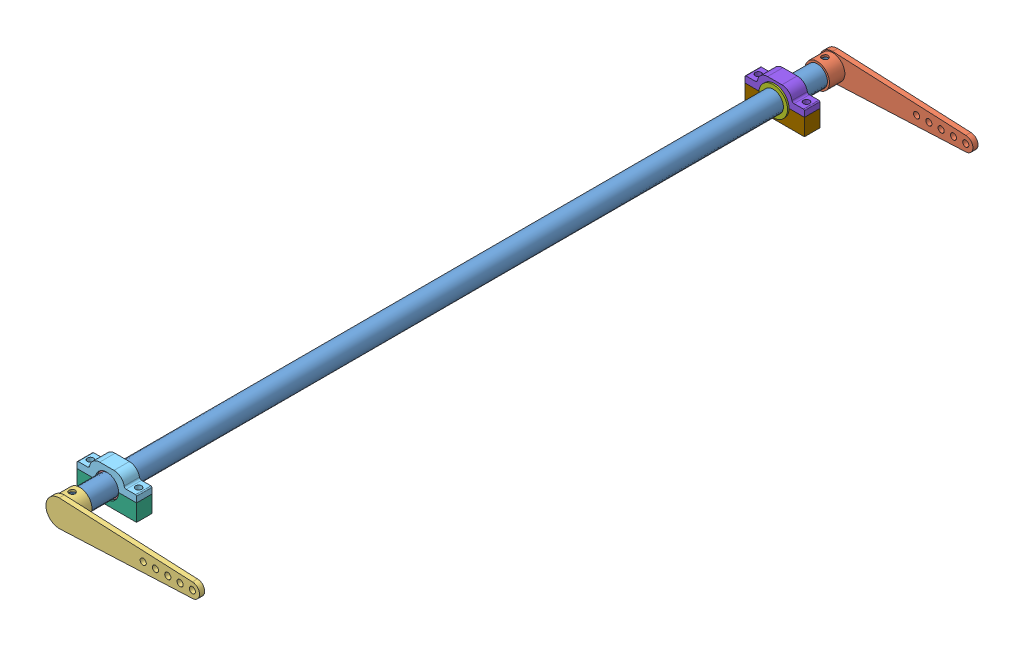
SolidWorks assembly 01101100-1-00, configuration Domyślna. Lengths in mm.
Overall size (166 36.59 760).
9 component instances, 9 part files, 20 mates.
Components (placement in the parent):
- 01101110-1-00-1: 01101110-1-00 [Domyślna] at (-3.3428 0.1273 400) size (20 20 750)
- 01101120-1-00-1: 01101120-1-00 [Domyślna] at (-3.3428 0.1273 395) size (150 26 20)
- 01101130-1-00-1: 01101130-1-00 [Domyślna] at (-3.3428 0.1273 1155) x (1 0 0) z (0 0 -1) size (150 26 20)
- 01101160-1-01-1: 01101160-1-01 [Domyślna] at (-3.3428 0.1273 1092) size (28 28 15)
- 01101170-1-01-1: 01101170-1-01 [Domyślna] at (-3.3428 0.1273 1093.5) size (58 16.5 15)
- 01101180-1-01-1: 01101180-1-01 [Domyślna] at (-3.3428 0.1273 1093.5) size (58 16.5 15)
- 01101160-1-02-1: 01101160-1-02 [Domyślna] at (-3.3428 0.1273 458) x (-0.923728 -0.383049 0) z (0 0 -1) size (28 28 15)
- 01101170-1-02-1: 01101170-1-02 [Domyślna] at (-3.3428 0.1273 456.5) x (-1 0 0) z (0 0 -1) size (58 16.5 15)
- 01101180-1-02-1: 01101180-1-02 [Domyślna] at (-3.3428 0.1273 456.5) x (-1 0 0) z (0 0 -1) size (58 16.5 15)
Mates (geometry in assembly coordinates):
- Koncentryczne1: concentric anti-aligned: cylinder of 01101110-1-00-1 through (-3.3428 0.1273 1150) axis (0 0 -1) radius 10; cylinder of 01101120-1-00-1 through (-3.3428 0.1273 400) axis (0 0 1) radius 10
- Koncentryczne2: concentric aligned: cylinder of 01101110-1-00-1 through (-3.3428 -9.8727 407.5) axis (0 1 0) radius 3; cylinder of 01101120-1-00-1 through (-3.3428 -21.3727 407.5) axis (0 1 0) radius 3
- Koncentryczne4: concentric aligned: cylinder of 01101110-1-00-1 through (-3.3428 0.1273 1150) axis (0 0 -1) radius 10; cylinder of 01101130-1-00-1 through (-3.3428 0.1273 1150) axis (0 0 -1) radius 10
- Concentric1: concentric anti-aligned: cylinder of 01101110-1-00-1 through (-3.3428 -9.8727 1142.5) axis (0 1 0) radius 3; cylinder of 01101130-1-00-1 through (-3.3428 21.6273 1142.5) axis (0 -1 0) radius 3
- Koncentryczne5: concentric aligned: cylinder of 01101170-1-01-1 through (-26.8428 6.6273 1101) axis (0 1 0) radius 3; cylinder of 01101180-1-01-1 through (-26.8428 0.1273 1101) axis (0 1 0) radius 3
- Koncentryczne6: concentric aligned: cylinder of 01101170-1-01-1 through (20.1572 6.6273 1101) axis (0 1 0) radius 3; cylinder of 01101180-1-01-1 through (20.1572 0.1273 1101) axis (0 1 0) radius 3
- Wspólnie1: coincident anti-aligned: plane of 01101170-1-01-1 through (8.1572 0.1273 1108.5) normal (0 -1 0); plane of 01101180-1-01-1 through (25.6572 0.1273 1108.5) normal (0 1 0)
- Koncentryczne7: concentric aligned: cylinder of 01101160-1-01-1 through (-3.3428 0.1273 1107) axis (0 0 -1) radius 11.5; cylinder of 01101180-1-01-1 through (-3.3428 0.1273 1108.5) axis (0 0 -1) radius 11.5
- Wspólnie2: coincident anti-aligned: plane of 01101160-1-01-1 through (-3.3428 0.1273 1093.5) normal (0 0 1); plane of 01101170-1-01-1 through (-3.3428 0.1273 1093.5) normal (0 0 -1)
- Koncentryczne8: concentric aligned: cylinder of 01101110-1-00-1 through (-3.3428 0.1273 1150) axis (0 0 -1) radius 10; cylinder of 01101160-1-01-1 through (-3.3428 0.1273 1107) axis (0 0 -1) radius 10
- Koncentryczne9: concentric aligned: cylinder of 01101170-1-02-1 through (20.1572 6.6273 449) axis (0 1 0) radius 3; cylinder of 01101180-1-02-1 through (20.1572 0.1273 449) axis (0 1 0) radius 3
- Koncentryczne10: concentric aligned: cylinder of 01101170-1-02-1 through (-26.8428 6.6273 449) axis (0 1 0) radius 3; cylinder of 01101180-1-02-1 through (-26.8428 0.1273 449) axis (0 1 0) radius 3
- Wspólnie3: coincident anti-aligned: plane of 01101170-1-02-1 through (-14.8428 0.1273 441.5) normal (0 -1 0); plane of 01101180-1-02-1 through (-32.3428 0.1273 441.5) normal (0 1 0)
- Koncentryczne11: concentric aligned: cylinder of 01101160-1-02-1 through (-3.3428 0.1273 443) axis (0 0 1) radius 10; cylinder of 01101180-1-02-1 through (-3.3428 0.1273 441.5) axis (0 0 1) radius 11.5
- Wspólnie4: coincident anti-aligned: plane of 01101160-1-02-1 through (-3.3428 0.1273 456.5) normal (0 0 -1); plane of 01101170-1-02-1 through (-3.3428 0.1273 456.5) normal (0 0 1)
- Koncentryczne13: concentric anti-aligned: cylinder of 01101110-1-00-1 through (-3.3428 0.1273 1150) axis (0 0 -1) radius 10; cylinder of 01101160-1-02-1 through (-3.3428 0.1273 443) axis (0 0 1) radius 10
- Odległość1: distance = 318.5 mm: plane of assembly through (0 0 775) normal (0 0 1); plane of assembly; plane of 01101180-1-02-1 through (-3.3428 0.1273 456.5) normal (0 0 1)
- Odległość2: distance = 318.5 mm anti-aligned: plane of 01101180-1-01-1 through (-3.3428 0.1273 1093.5) normal (0 0 -1)
- Równolegle1: parallel anti-aligned: plane of 01101180-1-02-1 through (25.6572 -16.3727 441.5) normal (0 -1 0)
- Równolegle2: parallel anti-aligned: plane of 01101180-1-01-1 through (-32.3428 -16.3727 1108.5) normal (0 -1 0)
